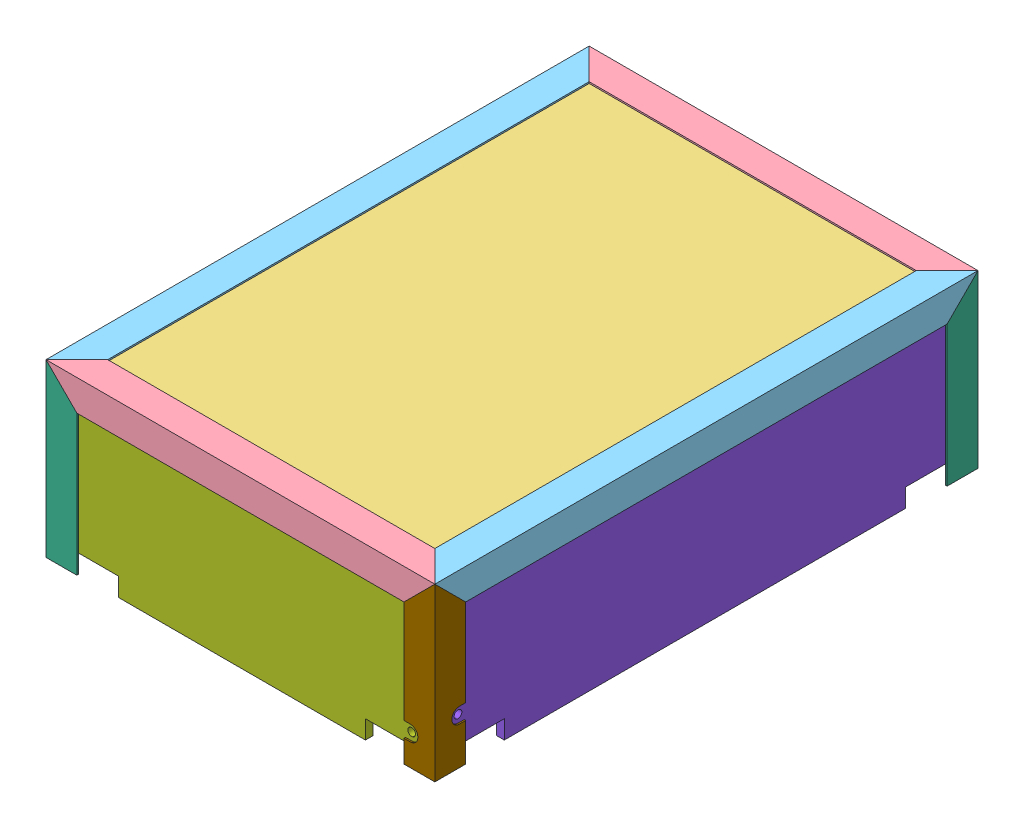
SolidWorks assembly couvercle, configuration Défaut. Lengths in mm.
Overall size (504 222 704).
13 component instances, 9 part files, 31 mates.
Components (placement in the parent):
- plaque_acrylique_680x210-2: plaque_acrylique_680x210 [Défaut] at (-487.4996 -8.7215 -345) x (0 0 -1) z (1 0 0) size (680 210 10)
- plaque_acrylique_380x210-2: plaque_acrylique_380x210 [Défaut] at (-187.4996 -8.7215 -695) size (480 210 10)
- plaque_acrylique_380x680-1: plaque_acrylique_380x680 [Défaut] at (-187.4996 96.2785 -345) x (1 0 0) z (0 1 0) size (480 680 10)
- eclisse_40x40x404_bisote_x2-1: eclisse_40x40x404_bisote_x2 [Défaut] at (14.5004 88.1649 -677) x (0 0 1) z (0 -1 0) size (40 504 40)
- eclisse_40x40x704_bisote_x2-1: eclisse_40x40x704_bisote_x2 [Défaut] at (-5.6132 88.2785 -697) x (0 -1 0) z (-1 0 0) size (40 704 40)
- eclisse_40x40x404_bisote_x2-2: eclisse_40x40x404_bisote_x2 [Défaut] at (-489.4996 88.1649 -13) x (0 0 -1) z (0 -1 0) size (40 504 40)
- eclisse_40x40x704_bisote_x2-2: eclisse_40x40x704_bisote_x2 [Défaut] at (-469.4996 88.1649 -697) x (1 0 0) z (0 -1 0) size (40 704 40)
- eclisse_40x40x222_bisote_x1-1: eclisse_40x40x222_bisote_x1 [Défaut] at (-469.386 108.2785 -677) x (0 0 1) z (1 0 0) size (40 222 40)
- eclisse_40x40x222_bisote_x1-2: eclisse_40x40x222_bisote_x1 [Défaut] at (-5.4996 108.2785 -676.8864) x (-1 0 0) z (0 0 1) size (40 222 40)
- eclisse_40x40x222_bisote_x1-4: eclisse_40x40x222_bisote_x1 [Défaut] at (-469.4996 108.2785 -13.1136) x (1 0 0) z (0 0 -1) size (40 222 40)
- plaque_acrylique_380x210_Moteur-1: plaque_acrylique_380x210_Moteur [Défaut] at (-187.4996 -8.7215 -5) size (480 210 10)
- plaque_acrylique_680x210_moteur-1: plaque_acrylique_680x210_moteur [Défaut] at (2.5004 -8.7215 -345) x (0 0 -1) z (1 0 0) size (680 210 10)
- eclisse_40x40x222_bisote_x1_Moteur-1: eclisse_40x40x222_bisote_x1_Moteur [Défaut] at (-5.6132 108.2785 -13) x (0 0 -1) z (-1 0 0) size (40 222 40)
Mates (geometry in assembly coordinates):
- Coïncidente5: coincident anti-aligned: plane of plaque_acrylique_680x210-2 through (-477.4996 -8.7215 -345) normal (1 0 0); plane of plaque_acrylique_380x210-2 through (-477.4996 96.2785 -685) normal (-1 0 0)
- Coïncidente6: coincident anti-aligned: plane of plaque_acrylique_680x210-2 through (-477.4996 96.2785 -685) normal (0 0 -1); plane of plaque_acrylique_380x210-2 through (-187.4996 -8.7215 -685) normal (0 0 1)
- Coïncidente12: coincident anti-aligned: plane of plaque_acrylique_680x210-2 through (-477.4996 96.2785 -5) normal (0 1 0); plane of plaque_acrylique_380x680-1 through (-187.4996 96.2785 -345) normal (0 -1 0)
- Coïncidente14: coincident anti-aligned: plane of plaque_acrylique_380x210-2 through (-187.4996 -8.7215 -685) normal (0 0 1); plane of plaque_acrylique_380x680-1 through (-477.4996 106.2785 -685) normal (0 0 -1)
- Coïncidente15: coincident anti-aligned: plane of plaque_acrylique_380x680-1 through (-187.4996 106.2785 -345) normal (0 1 0); plane of eclisse_40x40x704_bisote_x2-2 through (-487.4996 106.2785 7) normal (0 -1 0)
- Coïncidente16: coincident anti-aligned: plane of plaque_acrylique_380x680-1 through (-187.4996 106.2785 -345) normal (0 1 0); plane of eclisse_40x40x704_bisote_x2-1 through (12.5004 106.2785 7) normal (0 -1 0)
- Coïncidente18: coincident anti-aligned: plane of plaque_acrylique_680x210-2 through (-487.4996 -8.7215 -345) normal (-1 0 0); plane of eclisse_40x40x704_bisote_x2-2 through (-487.4996 106.2785 7) normal (1 0 0)
- Coïncidente19: coincident anti-aligned: plane of plaque_acrylique_380x680-1 through (-187.4996 106.2785 -345) normal (0 1 0); plane of eclisse_40x40x404_bisote_x2-2 through (14.5004 106.2785 5) normal (0 -1 0)
- Coïncidente21: coincident anti-aligned: plane of plaque_acrylique_380x680-1 through (-187.4996 106.2785 -345) normal (0 1 0); plane of eclisse_40x40x404_bisote_x2-1 through (-489.4996 106.2785 -695) normal (0 -1 0)
- Coïncidente22: coincident anti-aligned: plane of plaque_acrylique_380x210-2 through (-187.4996 -8.7215 -695) normal (0 0 -1); plane of eclisse_40x40x404_bisote_x2-1 through (-489.4996 106.2785 -695) normal (0 0 1)
- Coïncidente25: coincident anti-aligned: plane of eclisse_40x40x404_bisote_x2-1 through (-489.4996 68.2785 -697) normal (-0.707107 0 0.707107); plane of eclisse_40x40x704_bisote_x2-2 through (-489.4996 -481.7215 -697) normal (0.707107 0 -0.707107)
- Coïncidente28: coincident: point of eclisse_40x40x404_bisote_x2-1; point of eclisse_40x40x704_bisote_x2-2
- Coïncidente29: coincident anti-aligned: plane of eclisse_40x40x404_bisote_x2-1 through (14.5004 -481.7215 -697) normal (0.707107 0 0.707107); plane of eclisse_40x40x704_bisote_x2-1 through (14.5004 -481.7215 -697) normal (-0.707107 0 -0.707107)
- Coïncidente30: coincident anti-aligned: plane of eclisse_40x40x704_bisote_x2-1 through (14.5004 68.2785 7) normal (-0.707107 0 0.707107); plane of eclisse_40x40x404_bisote_x2-2 through (14.5004 68.2785 7) normal (0.707107 0 -0.707107)
- Coïncidente31: coincident anti-aligned: plane of eclisse_40x40x704_bisote_x2-2 through (100.5004 108.2785 -697) normal (0 -0.707107 -0.707107); plane of eclisse_40x40x222_bisote_x1-1 through (100.5004 108.2785 -697) normal (0 0.707107 0.707107)
- Coïncidente33: coincident aligned: plane of eclisse_40x40x404_bisote_x2-1 through (-489.4996 108.2785 -697) normal (0 0 -1); plane of eclisse_40x40x222_bisote_x1-1 through (-489.4996 -113.7215 -697) normal (0 0 -1)
- Coïncidente34: coincident anti-aligned: plane of eclisse_40x40x404_bisote_x2-1 through (-489.4996 108.2785 -657) normal (-0.707107 -0.707107 0); plane of eclisse_40x40x222_bisote_x1-1 through (-489.4996 108.2785 -107) normal (0.707107 0.707107 0)
- Coïncidente35: coincident aligned: plane of eclisse_40x40x404_bisote_x2-1 through (-489.4996 108.2785 -697) normal (0 0 -1); plane of eclisse_40x40x222_bisote_x1-2 through (14.5004 -113.7215 -697) normal (0 0 -1)
- Coïncidente36: coincident anti-aligned: plane of eclisse_40x40x404_bisote_x2-1 through (14.5004 108.2785 -107) normal (0.707107 -0.707107 0); plane of eclisse_40x40x222_bisote_x1-2 through (14.5004 108.2785 -107) normal (-0.707107 0.707107 0)
- Coïncidente37: coincident aligned: plane of eclisse_40x40x704_bisote_x2-1 through (14.5004 108.2785 7) normal (1 0 0); plane of eclisse_40x40x222_bisote_x1-2 through (14.5004 -113.7215 -697) normal (1 0 0)
- Coïncidente41: coincident aligned: plane of eclisse_40x40x704_bisote_x2-2 through (-489.4996 108.2785 7) normal (-1 0 0); plane of eclisse_40x40x222_bisote_x1-4 through (-489.4996 -113.7215 7) normal (-1 0 0)
- Coïncidente42: coincident anti-aligned: plane of eclisse_40x40x704_bisote_x2-2 through (-449.4996 108.2785 7) normal (0 -0.707107 0.707107); plane of eclisse_40x40x222_bisote_x1-4 through (100.5004 108.2785 7) normal (0 0.707107 -0.707107)
- Coïncidente43: coincident aligned: plane of eclisse_40x40x404_bisote_x2-2 through (14.5004 108.2785 7) normal (0 0 1); plane of eclisse_40x40x222_bisote_x1-4 through (-489.4996 -113.7215 7) normal (0 0 1)
- Coïncidente45: coincident anti-aligned: plane of plaque_acrylique_380x680-1 through (-187.4996 96.2785 -345) normal (0 -1 0); plane of plaque_acrylique_380x210_Moteur-1 through (-477.4996 96.2785 5) normal (0 1 0)
- Coïncidente46: coincident aligned: line of plaque_acrylique_680x210-2 through (-477.4996 96.2785 -5) axis (0 -1 0); line of plaque_acrylique_380x210_Moteur-1 through (-477.4996 96.2785 -5) axis (0 -1 0)
- Coïncidente47: coincident anti-aligned: plane of eclisse_40x40x222_bisote_x1-2 through (12.5004 -113.7215 -695) normal (-1 0 0); plane of plaque_acrylique_680x210_moteur-1 through (12.5004 -8.7215 -345) normal (1 0 0)
- Coïncidente48: coincident anti-aligned: plane of plaque_acrylique_380x680-1 through (-187.4996 96.2785 -345) normal (0 -1 0); plane of plaque_acrylique_680x210_moteur-1 through (12.5004 96.2785 -5) normal (0 1 0)
- Coïncidente49: coincident anti-aligned: line of plaque_acrylique_380x210_Moteur-1 through (2.5004 -89.7215 -5) axis (0 1 0); line of plaque_acrylique_680x210_moteur-1 through (2.5004 96.2785 -5) axis (0 -1 0)
- Coïncidente53: coincident anti-aligned: plane of plaque_acrylique_680x210_moteur-1 through (12.5004 -8.7215 -345) normal (1 0 0); plane of eclisse_40x40x222_bisote_x1_Moteur-1 through (12.5004 -113.7215 5) normal (-1 0 0)
- Coïncidente54: coincident anti-aligned: plane of plaque_acrylique_380x210_Moteur-1 through (-187.4996 -8.7215 5) normal (0 0 1); plane of eclisse_40x40x222_bisote_x1_Moteur-1 through (12.5004 -113.7215 5) normal (0 0 -1)
- Coïncidente55: coincident anti-aligned: plane of eclisse_40x40x404_bisote_x2-2 through (14.5004 108.2785 -33) normal (0.707107 -0.707107 0); plane of eclisse_40x40x222_bisote_x1_Moteur-1 through (14.5004 108.2785 -583) normal (-0.707107 0.707107 0)
